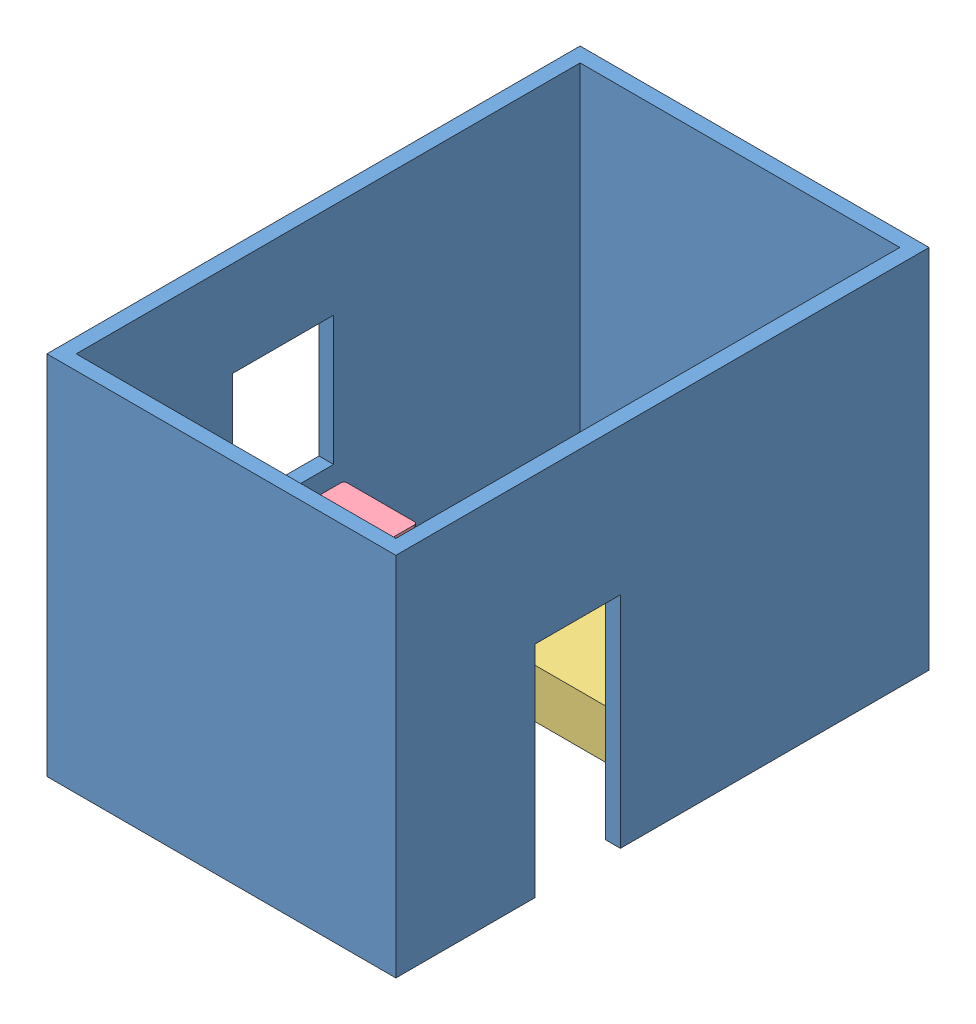
SolidWorks assembly house, configuration 默认. Lengths in mm.
Overall size (2860 3000 4370).
6 component instances, 5 part files, 16 mates.
Components (placement in the parent):
- wall-1: wall [默认] at origin size (2860 3000 4370)
- light-1: light [默认] at (-1310 2300 0) x (0 0 -1) z (1 0 0) size (100 80 1000)
- bed-1: bed [默认] at (-60 400 -2270) x (0 0 1) z (-1 0 0) size (1800 1000 2060)
- dresser-1: dresser [默认] at (-2320 1000 -1695) size (600 1000 1000)
- chest-1: chest [默认] at (-600 80 -300) x (0 0 -1) z (1 0 0) size (600 2080 1200)
- chest-2: chest [默认] at (-1800 80 -300) x (0 0 -1) z (1 0 0) size (600 2080 1200)
Mates (geometry in assembly coordinates):
- 重合1: coordinate: point of wall-1; point of assembly
- 重合2: coincident anti-aligned: plane of wall-1 through (0 3000 0) normal (0 0 -1); plane of light-1 through (-1310 2300 0) normal (0 0 1)
- 重合3: coincident: moEndPointRef_w of wall-1; plane of light-1 through (-1310 2300 0) normal (1 0 0)
- 距离1: distance = 2260 mm aligned: plane of light-1 through (-810 2260 -20) normal (0 -1 0); plane of wall-1 through (0 0 0) normal (0 -1 0)
- 重合5: coincident anti-aligned: plane of wall-1 through (0 3000 0) normal (-1 0 0); plane of bed-1 through (0 900 -2370) normal (1 0 0)
- 距离2: distance = 60 mm anti-aligned: plane of bed-1 through (-60 0 -4070) normal (0 0 -1); plane of wall-1 through (0 3000 -4130) normal (0 0 1)
- 重合7: coincident aligned: plane of wall-1 through (0 0 0) normal (0 -1 0); plane of bed-1 through (-60 0 -2270) normal (0 -1 0)
- 重合11: coincident anti-aligned: plane of wall-1 through (-2620 3000 0) normal (1 0 0); plane of dresser-1 through (-2620 700 -1195) normal (-1 0 0)
- 重合12: coincident aligned: plane of wall-1 through (0 0 0) normal (0 -1 0); plane of dresser-1 through (-2045 0 -1220) normal (0 -1 0)
- 重合13: coincident: moEndPointRef_w of wall-1; plane of dresser-1 through (-2320 1000 -1695) normal (0 0 1)
- 重合14: coincident anti-aligned: plane of wall-1 through (0 3000 0) normal (0 0 -1); plane of chest-1 through (0 2080 0) normal (0 0 1)
- 重合15: coincident anti-aligned: plane of wall-1 through (0 3000 0) normal (-1 0 0); plane of chest-1 through (0 2080 0) normal (1 0 0)
- 重合16: coincident aligned: plane of wall-1 through (0 0 0) normal (0 -1 0); plane of chest-1 through (-25 0 -575) normal (0 -1 0)
- 重合17: coincident aligned: plane of chest-1 through (0 2080 0) normal (0 0 1); plane of chest-2 through (-1200 2080 0) normal (0 0 1)
- 重合18: coincident aligned: plane of chest-1 through (-600 2080 -300) normal (0 1 0); plane of chest-2 through (-1800 2080 -300) normal (0 1 0)
- 重合19: coincident anti-aligned: plane of chest-1 through (-1200 2080 0) normal (-1 0 0); plane of chest-2 through (-1200 2080 0) normal (1 0 0)
